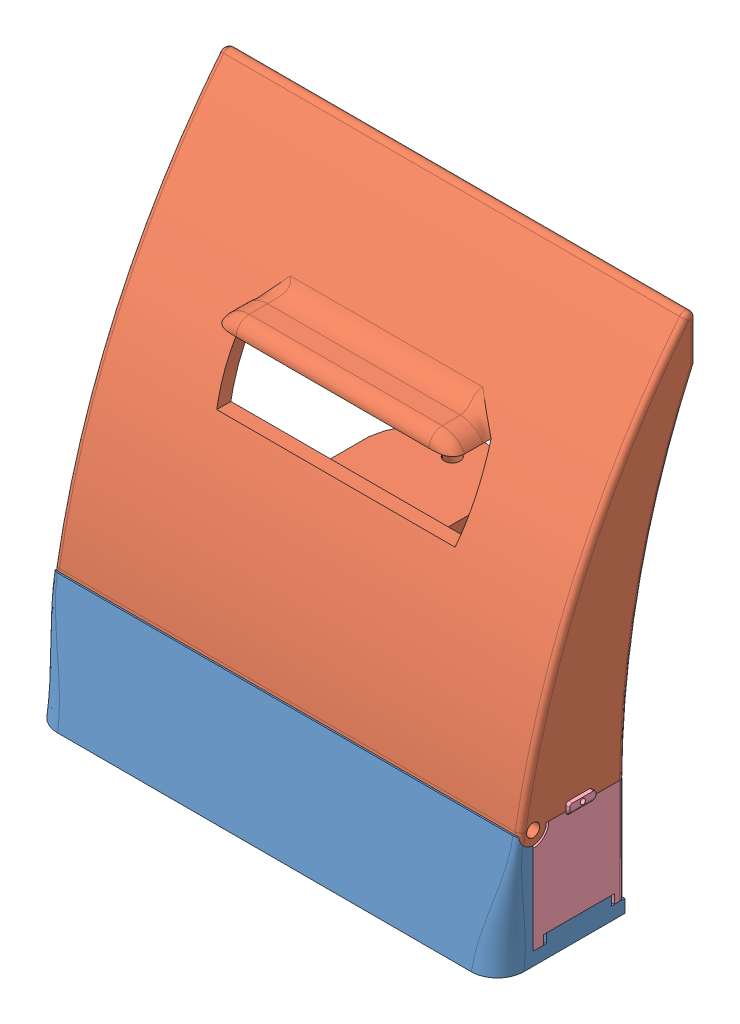
SolidWorks assembly front assembly 2, configuration Default. Lengths in mm.
Overall size (181 187.95 83.28).
4 component instances, 4 part files, 9 mates.
Components (placement in the parent):
- Foldable front base 2-1: Foldable front base 2 [Default] at (158.3211 77.8479 159.546) size (179.15 51.76 49.18)
- foldable front flap 2-1: foldable front flap 2 [Default] at (69.3211 122.8479 151.0232) x (-1 0 0) z (0 0 -1) size (178.61 145.94 74.18)
- Foldable front side flap right 2-1: Foldable front side flap right 2 [Default] at (-17.1789 86.3479 110.946) x (0 0 1) z (-1 0 0) size (35 43 8.5)
- Foldable front side flap left 2-1: Foldable front side flap left 2 [Default] at (155.8211 86.3479 145.946) x (0 0 -1) z (1 0 0) size (35 43 8.5)
Mates (geometry in assembly coordinates):
- Concentric1: concentric: cylinder of Foldable front base 2-1 through (-19.6789 122.8479 145.946) axis (1 0 0) radius 2.5; cylinder of foldable front flap 2-1 through (158.3211 122.8479 145.946) axis (-1 0 0) radius 2.5
- Distance1: distance = 1 mm: plane of foldable front flap 2-1 through (-14.6789 122.8479 145.946) normal (1 0 0); plane of Foldable front base 2-1 through (-13.6789 122.8479 145.946) normal (-1 0 0)
- Concentric2: concentric: cylinder of Foldable front base 2-1 through (154.8211 86.3479 140.946) axis (0 0 -1) radius 2.5; cylinder of Foldable front side flap left 2-1 through (154.8211 86.3479 114.946) axis (0 0 -1) radius 2.5
- Distance2: distance = 1 mm: plane of Foldable front base 2-1 through (158.3211 77.8479 115.946) normal (0 0 -1); plane of Foldable front side flap left 2-1 through (155.8211 86.3479 114.946) normal (0 0 1)
- Concentric3: concentric: cylinder of Foldable front base 2-1 through (-16.1789 86.3479 140.946) axis (0 0 -1) radius 2.5; cylinder of Foldable front side flap right 2-1 through (-16.1789 86.3479 114.946) axis (0 0 -1) radius 2.5
- Distance3: distance = 1 mm: plane of Foldable front side flap right 2-1 through (-17.1789 86.3479 141.946) normal (0 0 -1); plane of Foldable front base 2-1 through (158.3211 77.8479 140.946) normal (0 0 1)
- Coincident1: coincident: plane of Foldable front base 2-1 through (158.3211 122.8479 159.546) normal (1 0 0); plane of Foldable front side flap left 2-1 through (158.3211 86.3479 145.946) normal (1 0 0)
- Coincident2: coincident: plane of Foldable front base 2-1 through (-19.6789 122.8479 159.546) normal (-1 0 0); plane of Foldable front side flap right 2-1 through (-19.6789 86.3479 110.946) normal (-1 0 0)
- Coincident3: coincident: plane of foldable front flap 2-1 through (-14.6789 122.8479 140.946) normal (0 -1 0); plane of Foldable front side flap right 2-1 through (-19.6789 122.8479 110.946) normal (0 1 0)
